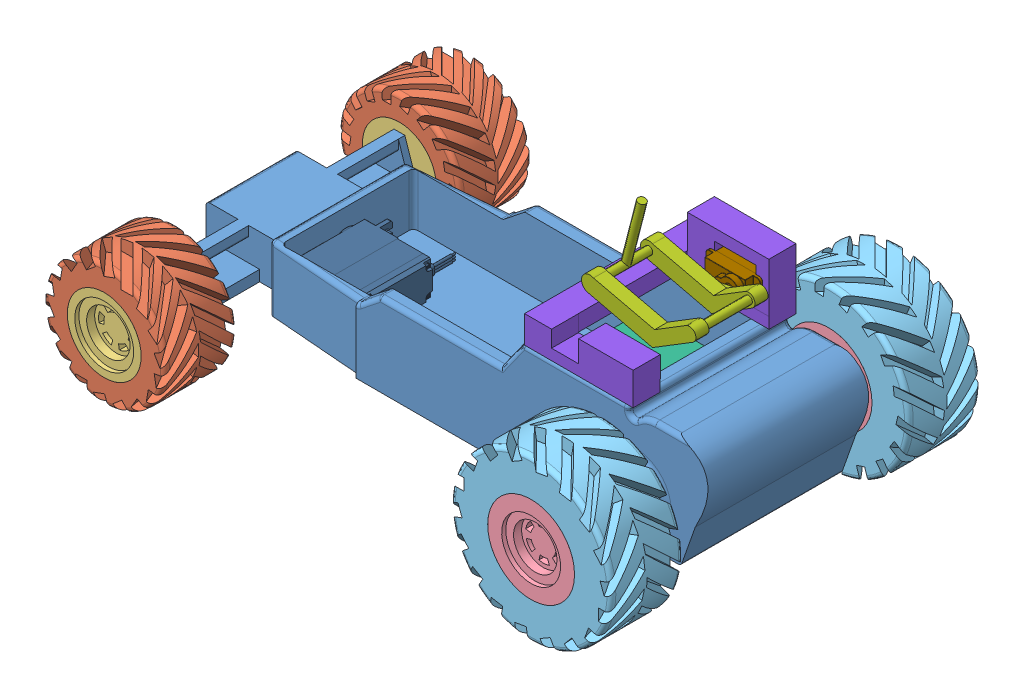
SolidWorks assembly Rover Assembly - Mission 1A, configuration Default. Lengths in mm.
Overall size (358.33 182.12 216.47).
18 component instances, 10 part files, 28 mates.
Components (placement in the parent):
- Rover Body-1: Rover Body [Default] at (350.1991 140.944 194.7701) size (315.02 66.04 157.48)
- Front Wheel Assembly-1: Front Wheel Assembly [Default] at (-17.2731 108.0697 201.579) size (71.72 71.61 42.52)
  - Tire 1-2: Tire 1 [Default] at (19.9119 41.7643 105.936) size (71.72 71.61 42.52)
  - Front Wheel Hub-1: Front Wheel Hub [Default] at (19.9119 41.7643 126.891) size (43.18 43.18 41.91)
- Front Wheel Assembly-2: Front Wheel Assembly [Default] at (-23.229 111.4726 282.7561) x (-0.507799 0.861476 0) z (0 0 -1) size (71.72 71.61 42.52)
  - Tire 1-2: Tire 1 [Default] at (19.9119 41.7643 105.936) size (71.72 71.61 42.52)
  - Front Wheel Hub-1: Front Wheel Hub [Default] at (19.9119 41.7643 126.891) size (43.18 43.18 41.91)
- Rear Wheel Assembly-1: Rear Wheel Assembly [Default] at (302.7473 220.8573 238.2426) x (-0.985068 0.172166 0) z (0 0 1) size (94.56 94.48 42.49)
  - Rear Wheel Hub-1: Rear Wheel Hub [Default] at (39.9984 62.3303 90.5124) x (0.280155 -0.959955 0) z (0 0 1) size (50.8 50.8 41.91)
  - Rear Tire-2: Rear Tire [Default] at (39.9984 62.3303 69.5574) size (94.56 94.48 42.49)
- Rear Wheel Assembly-2: Rear Wheel Assembly [Default] at (309.5078 118.9295 245.2775) x (-0.9537 -0.300759 0) z (0 0 -1) size (94.56 94.48 42.49)
  - Rear Wheel Hub-1: Rear Wheel Hub [Default] at (39.9984 62.3303 90.5124) x (0.280155 -0.959955 0) z (0 0 1) size (50.8 50.8 41.91)
  - Rear Tire-2: Rear Tire [Default] at (39.9984 62.3303 69.5574) size (94.56 94.48 42.49)
- Arduino- Motor Shield-1: Arduino- Motor Shield [Default] at (206.4479 173.964 230.1641) x (0 0 1) z (0 -1 0) size (53.34 68.58 25.4)
- Payload Arm-1: Payload Arm [Default] at (259.8738 236.542 264.3791) x (0 0 -1) z (0.851732 0.523978 0) size (44.7 58.77 60.43)
- Payload Dump Part 1-1: Payload Dump Part 1 [Default] at (219.5764 206.984 241.1251) x (-1 0 0) z (0 0 -1) size (63.5 35.56 95.25)
- Servo ES08MDII v2.step-1: Servo ES08MDII v2.step [Default] at (231.9564 225.5559 195.1751) size (31.7 11.5 27.8)
- FT5835M-1: FT5835M [Standard] at (79.5635 158.563 273.592) x (0 0 -1) z (0 1 0) size (64.95 47.15 20.11)
Mates (geometry in assembly coordinates):
- Concentric1: concentric aligned: cylinder of Rover Body-1 through (252.615 166.344 320.5001) axis (0 0 -1) radius 4.445; circle of Rear Wheel Assembly-1/Rear Wheel Hub-1
- Coincident2: coincident anti-aligned: plane of Rover Body-1 through (252.615 166.344 307.8001) normal (0 0 1); plane of Rear Wheel Assembly-1/Rear Wheel Hub-1 through (252.615 166.344 307.8001) normal (0 0 -1)
- Concentric2: concentric aligned: cylinder of Rover Body-1 through (252.615 166.344 163.0201) axis (0 0 1) radius 4.445; cylinder of Rear Wheel Assembly-2/Rear Wheel Hub-1 through (252.615 166.344 155.9081) axis (0 0 1) radius 4.445
- Coincident3: coincident anti-aligned: plane of Rover Body-1 through (252.615 166.344 175.7201) normal (0 0 -1); plane of Rear Wheel Assembly-2/Rear Wheel Hub-1 through (252.615 166.344 175.7201) normal (0 0 1)
- Coincident6: coincident anti-aligned: plane of Rover Body-1 through (350.1991 148.564 194.7701) normal (0 1 0); plane of Arduino- Motor Shield-1 through (206.4479 148.564 230.1641) normal (0 -1 0)
- Coincident7: coincident anti-aligned: plane of Rover Body-1 through (240.7379 206.984 203.4941) normal (-1 0 0); plane of Arduino- Motor Shield-1 through (240.7379 148.564 256.8341) normal (1 0 0)
- Coincident8: coincident anti-aligned: plane of Rover Body-1 through (37.5635 206.984 203.4941) normal (0 0 1); plane of Arduino- Motor Shield-1 through (240.7379 148.564 203.4941) normal (0 0 -1)
- Parallel1: parallel aligned: plane of Payload Dump Part 1-1 through (219.5764 242.544 241.1251) normal (0 1 0); plane of Servo ES08MDII v2.step-1 through (243.7064 231.3059 195.1751) normal (0 1 0)
- Parallel2: parallel aligned: plane of Payload Dump Part 1-1 through (251.3264 242.544 193.5001) normal (1 0 0); plane of Servo ES08MDII v2.step-1 through (243.7064 219.8059 195.1751) normal (1 0 0)
- Coincident11: coincident anti-aligned: plane of Payload Dump Part 1-1 through (203.5744 206.984 209.3751) normal (0 0 1); plane of Servo ES08MDII v2.step-1 through (243.7064 231.3059 209.3751) normal (0 0 -1)
- Coincident12: coincident anti-aligned: plane of Payload Dump Part 1-1 through (243.7064 219.8059 288.7511) normal (0 1 0); plane of Servo ES08MDII v2.step-1 through (220.2064 219.8059 195.1751) normal (0 -1 0)
- Coincident13: coincident anti-aligned: plane of Payload Dump Part 1-1 through (243.7064 235.8079 288.7511) normal (-1 0 0); plane of Servo ES08MDII v2.step-1 through (243.7064 219.8059 195.1751) normal (1 0 0)
- Parallel3: parallel anti-aligned: plane of Payload Arm-1 through (201.072 228.6797 222.2151) normal (0 0 -1); plane of Payload Dump Part 1-1 through (203.5744 206.984 209.3751) normal (0 0 1)
- Concentric6: concentric aligned: cylinder of Payload Arm-1 through (237.9564 225.5559 222.2151) axis (0 0 -1) radius 1.905; cone of Servo ES08MDII v2.step-1 through (237.9564 225.5559 222.6751) axis (0 0 -1)
- Coincident16: coincident anti-aligned: plane of Payload Arm-1 through (258.6247 238.7426 219.6751) normal (0 0 -1); plane of Servo ES08MDII v2.step-1 through (237.9564 225.5559 219.6751) normal (0 0 1)
- Parallel6: parallel anti-aligned: plane of Arduino- Motor Shield-1 through (206.4479 173.964 230.1641) normal (0 1 0); plane of Payload Dump Part 1-1 through (219.5764 206.984 241.1251) normal (0 -1 0)
- Parallel8: parallel aligned: plane of Rover Body-1 through (240.7379 206.984 203.4941) normal (-1 0 0); plane of Payload Dump Part 1-1 through (187.8264 242.544 193.5001) normal (-1 0 0)
- Coincident27: coincident anti-aligned: plane of Rover Body-1 through (186.5193 206.984 288.7501) normal (0 1 0); plane of Payload Dump Part 1-1 through (219.5764 206.984 241.1251) normal (0 -1 0)
- Coincident28: coincident: line of Rover Body-1 through (187.8264 206.984 197.3101) axis (0 0 1); plane of Payload Dump Part 1-1 through (187.8264 242.544 193.5001) normal (-1 0 0)
- Coincident29: coincident: plane of Rover Body-1 through (294.5682 192.301 288.7501) normal (0 0 1); line of Payload Dump Part 1-1 through (187.8264 206.984 288.7501) axis (1 0 0)
- Parallel9: parallel anti-aligned: plane of Rover Body-1 through (350.1991 148.564 194.7701) normal (0 1 0); plane of FT5835M-1 through (47.5635 148.565 273.59) normal (0 -1 0)
- Coincident33: coincident anti-aligned: plane of Rover Body-1 through (350.1991 148.564 194.7701) normal (0 1 0); plane of FT5835M-1 through (58.2635 148.564 273.591) normal (0 -1 0)
- Coincident35: coincident anti-aligned: plane of Rover Body-1 through (37.5635 206.984 203.4941) normal (1 0 0); plane of FT5835M-1 through (37.5635 165.763 265.942) normal (-1 0 0)
- Coincident36: coincident anti-aligned: plane of Rover Body-1 through (37.5635 206.984 280.841) normal (0 0 -1); plane of FT5835M-1 through (45.0635 164.763 280.841) normal (0 0 1)
- Concentric7: concentric: cylinder of Rover Body-1 through (2.6387 149.834 320.5001) axis (0 0 -1) radius 4.445; cylinder of Front Wheel Assembly-1/Front Wheel Hub-1 through (2.6387 149.834 327.327) axis (0 0 -1) radius 4.445
- Coincident37: coincident anti-aligned: plane of Rover Body-1 through (-7.0127 147.294 307.515) normal (0 0 1); plane of Front Wheel Assembly-1/Front Wheel Hub-1 through (2.6387 149.834 307.515) normal (0 0 -1)
- Concentric8: concentric: cylinder of Rover Body-1 through (2.6387 149.834 163.0201) axis (0 0 1) radius 4.445; cylinder of Front Wheel Assembly-2/Front Wheel Hub-1 through (2.6387 149.834 157.0081) axis (0 0 1) radius 4.445
- Coincident38: coincident anti-aligned: plane of Rover Body-1 through (-7.0127 147.294 176.8201) normal (0 0 -1); plane of Front Wheel Assembly-2/Front Wheel Hub-1 through (2.6387 149.834 176.8201) normal (0 0 1)
